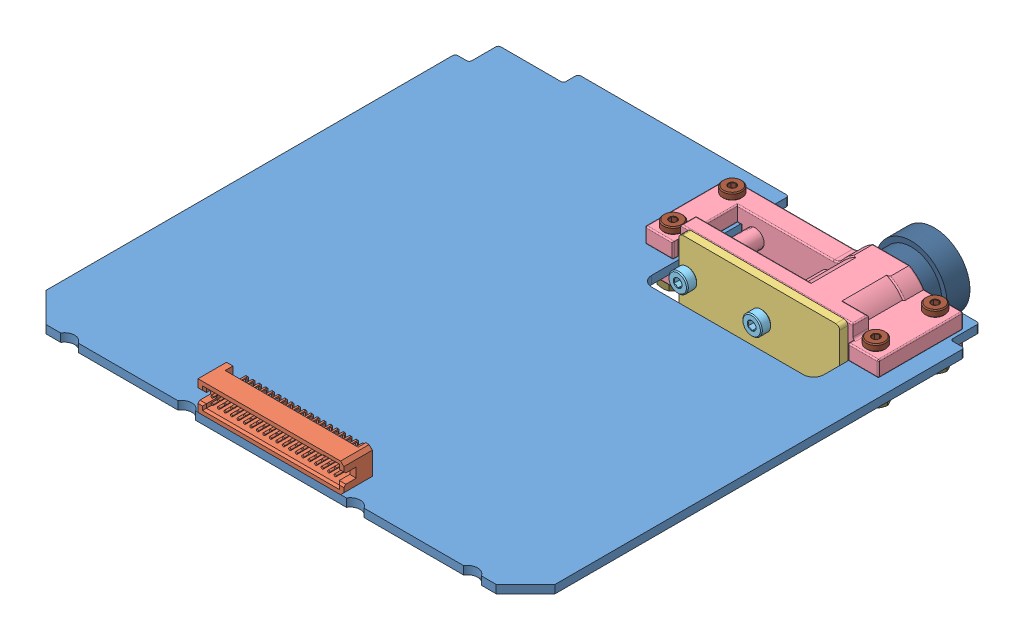
SolidWorks assembly StarTrackerCard, configuration Default. Lengths in mm.
Overall size (100 14.75 109.9).
21 component instances, 12 part files, 45 mates.
Components (placement in the parent):
- StarTrackerCard-1: StarTrackerCard [Default] at origin size (100 12.1 107.37)
- TFM_120_01_L_D_RA_defeature-1: TFM_120_01_L_D_RA_defeature [Default] at (0 3.6575 39.237) x (1 0 0) z (0 -1 0) size (28.58 7.49 7.62)
- startracker-2: startracker [Default] at (23.9 -0.05 -30.1) size (45.75 14.75 27.61)
  - startrackerboard-1: startrackerboard [Default] at (0 -0.2 2.3) x (-1 0 0) z (0 0 -1) size (31.5 13.6 1.6)
  - startrackerboardmount-1: startrackerboardmount [Default] x (-1 0 0) z (0 0 1) size (45.75 14.75 16.6)
  - 92290A850_SUPER-CORROSION-RST 316 SS SCKT HEAD SCREW-1: 92290A850_SUPER-CORROSION-RST 316 SS SCKT HEAD SCREW [92290A850] at (0.5 0 -14.9) x (1 0 0) z (0 0 -1) size (3.8 3.8 20.17)
  - 92290A850_SUPER-CORROSION-RST 316 SS SCKT HEAD SCREW-2: 92290A850_SUPER-CORROSION-RST 316 SS SCKT HEAD SCREW [92290A850] at (-14 0 -14.9) x (-1 0 0) z (0 0 -1) size (3.8 3.8 20.17)
  - 94150A115_316 STAINLESS STEEL HEX NUT-1: 94150A115_316 STAINLESS STEEL HEX NUT [94150A115] at (0.5 0 -13.05) x (-0.5 0.866025 0) z (0 0 1) size (3.2 3.7 1.58)
  - 94150A115_316 STAINLESS STEEL HEX NUT-2: 94150A115_316 STAINLESS STEEL HEX NUT [94150A115] at (-14 0 -13.05) x (0.5 0.866025 0) z (0 0 1) size (3.2 3.7 1.58)
  - ILCC48-1: ILCC48 [Default] at (8.75 0 1.5) x (-1 0 0) z (0 0 -1) size (4.8 3.6 0.72)
  - knifeedgebaffle-1: knifeedgebaffle [Default] at (8.75 0 -6.425) x (0 1 0) z (1 0 0) size (12 2 12)
  - ILCC48_cover-1: ILCC48_cover [Default] at (8.75 0 0.25) x (0 1 0) z (0 0 1) size (7 7 1.25)
  - startrackerNEW-1: startrackerNEW [Default] at (8.75 0 -20.925) x (-1 0 0) z (0 0 -1) size (14 14 16)
- 92855A840_18-8 SS LOW-PROFILE SCKT HEAD SCREWS-1: 92855A840_18-8 SS LOW-PROFILE SCKT HEAD SCREWS [92855A840] at (3.9 -6.15 -41.7) x (1 0 0) z (0 -1 0) size (3.8 3.8 11.46)
- 91828A111_TYPE 18-8 STAINLESS STEEL HEX NUT-2: 91828A111_TYPE 18-8 STAINLESS STEEL HEX NUT [91828A111] at (3.9 -4.75 -41.7) x (0.866025 0 0.5) z (0 -1 0) size (4 4.62 1.83)
- 92855A840_18-8 SS LOW-PROFILE SCKT HEAD SCREWS-5: 92855A840_18-8 SS LOW-PROFILE SCKT HEAD SCREWS [92855A840] at (43.65 -6.15 -41.7) x (1 0 0) z (0 -1 0) size (3.8 3.8 11.46)
- 92855A840_18-8 SS LOW-PROFILE SCKT HEAD SCREWS-6: 92855A840_18-8 SS LOW-PROFILE SCKT HEAD SCREWS [92855A840] at (3.9 -6.15 -30.1) x (1 0 0) z (0 -1 0) size (3.8 3.8 11.46)
- 92855A840_18-8 SS LOW-PROFILE SCKT HEAD SCREWS-7: 92855A840_18-8 SS LOW-PROFILE SCKT HEAD SCREWS [92855A840] at (43.65 -6.15 -30.1) x (1 0 0) z (0 -1 0) size (3.8 3.8 11.46)
- 91828A111_TYPE 18-8 STAINLESS STEEL HEX NUT-4: 91828A111_TYPE 18-8 STAINLESS STEEL HEX NUT [91828A111] at (43.65 -4.75 -41.7) x (0.866025 0 0.5) z (0 -1 0) size (4 4.62 1.83)
- 91828A111_TYPE 18-8 STAINLESS STEEL HEX NUT-5: 91828A111_TYPE 18-8 STAINLESS STEEL HEX NUT [91828A111] at (3.9 -4.75 -30.1) x (0.866025 0 0.5) z (0 -1 0) size (4 4.62 1.83)
- 91828A111_TYPE 18-8 STAINLESS STEEL HEX NUT-6: 91828A111_TYPE 18-8 STAINLESS STEEL HEX NUT [91828A111] at (43.65 -4.75 -30.1) x (0.866025 0 0.5) z (0 -1 0) size (4 4.62 1.83)
Mates (geometry in assembly coordinates):
- Coincident7: coincident: line of StarTrackerCard-1 through (0 0.8 -5.2282) axis (0 0 1); plane of TFM_120_01_L_D_RA_defeature-1 through (0 3.6575 39.237) normal (1 0 0)
- Coincident8: coincident anti-aligned: plane of StarTrackerCard-1 through (0 0.8 0) normal (0 1 0); plane of TFM_120_01_L_D_RA_defeature-1 through (-14.2875 0.8 44.825) normal (0 -1 0)
- Coincident9: coincident: line of StarTrackerCard-1 through (49.9 0.8 37.332) axis (-1 0 0); plane of TFM_120_01_L_D_RA_defeature-1 through (0 3.6575 37.332) normal (0 0 -1)
- Coincident10: coincident aligned: plane of StarTrackerCard-1 through (0 0 0) normal (0 0 1); plane of assembly through (0 0 0) normal (0 0 1)
- Coincident11: coincident aligned: plane of StarTrackerCard-1 through (0 0 0) normal (0 1 0); plane of assembly through (0 0 0) normal (0 1 0)
- Coincident12: coincident aligned: plane of StarTrackerCard-1 through (0 0 0) normal (1 0 0); plane of assembly through (0 0 0) normal (1 0 0)
- Coincident20: coincident anti-aligned: plane of StarTrackerCard-1 through (0 0.8 0) normal (0 1 0); plane of startracker-2/startrackerboardmount-1 through (23.9 0.8 -30.1) normal (0 -1 0)
- Concentric7: concentric anti-aligned: circle of 92290A602_TYPE 316 SS SOCKET HEAD CAP SCREW-2; circle of startracker-2/startrackerboardmount-1
- Coincident21: coincident anti-aligned: plane of 92290A602_TYPE 316 SS SOCKET HEAD CAP SCREW-2 through (3.9 3.8 -42.8) normal (0 -1 0); plane of startracker-2/startrackerboardmount-1 through (6.9 3.85 -28.6) normal (0 1 0)
- Concentric8: concentric anti-aligned: circle of 92290A602_TYPE 316 SS SOCKET HEAD CAP SCREW-1; circle of startracker-2/startrackerboardmount-1
- Coincident22: coincident anti-aligned: plane of 92290A602_TYPE 316 SS SOCKET HEAD CAP SCREW-1 through (3.9 3.8 -31.2) normal (0 -1 0); plane of startracker-2/startrackerboardmount-1 through (6.9 3.85 -28.6) normal (0 1 0)
- Parallel6: parallel anti-aligned: plane of StarTrackerCard-1 through (-34.4 -0.801 -49.8) normal (0 0 -1); plane of 92290A602_TYPE 316 SS SOCKET HEAD CAP SCREW-1 through (3.9 -6.2 -31.2) normal (0 0 1)
- Parallel7: parallel anti-aligned: plane of StarTrackerCard-1 through (-34.4 -0.801 -49.8) normal (0 0 -1); plane of 92290A602_TYPE 316 SS SOCKET HEAD CAP SCREW-2 through (3.9 -6.2 -42.8) normal (0 0 1)
- Coincident23: coincident anti-aligned: plane of 94150A115_316 STAINLESS STEEL HEX NUT-1 through (2.9762 -3.95 -32.8) normal (0 1 0); plane of startracker-2/startrackerboardmount-1 through (3.9 -3.95 -28.6) normal (0 -1 0)
- Concentric9: concentric anti-aligned: circle of 94150A115_316 STAINLESS STEEL HEX NUT-1; circle of startracker-2/startrackerboardmount-1
- Parallel9: parallel aligned: plane of StarTrackerCard-1 through (-34.4 -0.801 -49.8) normal (0 0 -1); plane of 94150A115_316 STAINLESS STEEL HEX NUT-1 through (4.8238 -3.95 -32.8) normal (0 0 -1)
- Concentric10: concentric anti-aligned: circle of 94150A115_316 STAINLESS STEEL HEX NUT-2; circle of startracker-2/startrackerboardmount-1
- Coincident24: coincident anti-aligned: plane of 94150A115_316 STAINLESS STEEL HEX NUT-2 through (2.9762 -3.95 -44.4) normal (0 1 0); plane of startracker-2/startrackerboardmount-1 through (3.9 -3.95 -28.6) normal (0 -1 0)
- Parallel10: parallel aligned: plane of StarTrackerCard-1 through (-34.4 -0.801 -49.8) normal (0 0 -1); plane of 94150A115_316 STAINLESS STEEL HEX NUT-2 through (4.8238 -3.95 -44.4) normal (0 0 -1)
- Distance3: distance = 3.25 mm aligned: plane of StarTrackerCard-1 through (49.9 -0.8 0) normal (1 0 0); plane of startracker-2/startrackerboardmount-1 through (46.65 -0.05 -20.8918) normal (1 0 0)
- Distance1: distance = 5.6 mm aligned: plane of startracker-2/startrackerboardmount-1 through (0.9 -9.3583 -44.2) normal (0 0 -1); plane of StarTrackerCard-1 through (-34.4 -0.801 -49.8) normal (0 0 -1)
- Coincident25: coincident anti-aligned: circle of startracker-2/startrackerboardmount-1; plane of 92290A602_TYPE 316 SS SOCKET HEAD CAP SCREW-4 through (43.65 3.85 -31.2) normal (0 -1 0)
- Concentric11: concentric anti-aligned: circle of startracker-2/startrackerboardmount-1; circle of 92290A602_TYPE 316 SS SOCKET HEAD CAP SCREW-4
- Concentric12: concentric: circle of startracker-2/startrackerboardmount-1; circle of 92290A602_TYPE 316 SS SOCKET HEAD CAP SCREW-3
- Coincident26: coincident anti-aligned: plane of startracker-2/startrackerboardmount-1 through (23.9 3.85 -20.8918) normal (0 1 0); plane of 92290A602_TYPE 316 SS SOCKET HEAD CAP SCREW-3 through (43.65 3.85 -42.8) normal (0 -1 0)
- Parallel11: parallel: plane of startracker-2/startrackerboardmount-1 through (0.9 -9.3583 -44.2) normal (0 0 -1); plane of 92290A602_TYPE 316 SS SOCKET HEAD CAP SCREW-3 through (43.65 -6.15 -42.8) normal (0 0 1)
- Concentric13: concentric anti-aligned: circle of startracker-2/startrackerboardmount-1; circle of 94150A115_316 STAINLESS STEEL HEX NUT-3
- Coincident29: coincident anti-aligned: plane of startracker-2/startrackerboardmount-1 through (23.9 -3.95 -21.8918) normal (0 -1 0); plane of 94150A115_316 STAINLESS STEEL HEX NUT-3 through (42.7262 -3.95 -44.4) normal (0 1 0)
- Concentric14: concentric aligned: circle of startracker-2/startrackerboardmount-1; circle of 94150A115_316 STAINLESS STEEL HEX NUT-4
- Coincident30: coincident anti-aligned: plane of startracker-2/startrackerboardmount-1 through (23.9 -3.95 -21.8918) normal (0 -1 0); plane of 94150A115_316 STAINLESS STEEL HEX NUT-4 through (42.7262 -3.95 -32.8) normal (0 1 0)
- Parallel13: parallel aligned: plane of startracker-2/startrackerboardmount-1 through (23.9 -0.05 -31.6) normal (0 0 -1); plane of 94150A115_316 STAINLESS STEEL HEX NUT-4 through (44.5738 -3.95 -32.8) normal (0 0 -1)
- Parallel14: parallel aligned: plane of startracker-2/startrackerboardmount-1 through (32.65 -0.05 -43.2) normal (0 0 -1); plane of 94150A115_316 STAINLESS STEEL HEX NUT-3 through (44.5738 -3.95 -44.4) normal (0 0 -1)
- Coincident31: coincident anti-aligned: plane of startracker-2/startrackerboardmount-1 through (6.9 3.85 -28.6) normal (0 1 0); plane of 92855A840_18-8 SS LOW-PROFILE SCKT HEAD SCREWS-1 through (3.9 3.85 -41.7) normal (0 -1 0)
- Concentric15: concentric aligned: circle of startracker-2/startrackerboardmount-1; circle of 92855A840_18-8 SS LOW-PROFILE SCKT HEAD SCREWS-1
- Coincident32: coincident anti-aligned: plane of startracker-2/startrackerboardmount-1 through (3.9 -3.95 -28.6) normal (0 -1 0); plane of 93625A101_TYPE 18-8 STAINLESS STL NYLON-INSERT LOCKNUT-1 through (7.469 -3.95 -44.6062) normal (0 1 0)
- Concentric16: concentric aligned: circle of startracker-2/startrackerboardmount-1; circle of 93625A101_TYPE 18-8 STAINLESS STL NYLON-INSERT LOCKNUT-1
- Parallel16: parallel aligned: plane of 92855A840_18-8 SS LOW-PROFILE SCKT HEAD SCREWS-1 through (3.9 -6.15 -41.7) normal (0 0 1)
- Coincident35: coincident anti-aligned: plane of startracker-2/startrackerboardmount-1 through (3.9 -3.95 -28.6) normal (0 -1 0); plane of 91828A111_TYPE 18-8 STAINLESS STEEL HEX NUT-1 through (2.7453 -3.95 -29.2) normal (0 1 0)
- Concentric17: concentric anti-aligned: circle of startracker-2/startrackerboardmount-1; circle of 91828A111_TYPE 18-8 STAINLESS STEEL HEX NUT-1
- Parallel17: parallel aligned: plane of startracker-2/startrackerboardmount-1 through (23.9 -22.2045 -27.6) normal (0 0 1); plane of 91828A111_TYPE 18-8 STAINLESS STEEL HEX NUT-1 through (5.0547 -5.55 -29.2) normal (0 0 1)
- Concentric18: concentric anti-aligned: circle of startracker-2/startrackerboardmount-1; circle of 92855A841_18-8 SS LOW-PROFILE SCKT HEAD SCREWS-1
- Coincident37: coincident anti-aligned: plane of startracker-2/startrackerboardmount-1 through (6.9 3.85 -28.6) normal (0 1 0); plane of 92855A841_18-8 SS LOW-PROFILE SCKT HEAD SCREWS-1 through (3.9 3.85 -31.2) normal (0 -1 0)
- Coincident38: coincident anti-aligned: plane of startracker-2/startrackerboardmount-1 through (3.9 -3.95 -28.6) normal (0 -1 0); plane of 91828A111_TYPE 18-8 STAINLESS STEEL HEX NUT-2 through (1.5906 -3.95 -41.7) normal (0 1 0)
- Concentric19: concentric anti-aligned: circle of startracker-2/startrackerboardmount-1; circle of 91828A111_TYPE 18-8 STAINLESS STEEL HEX NUT-2
- Parallel18: parallel aligned: plane of startracker-2/startrackerboardmount-1 through (0.9 -9.3583 -44.2) normal (0 0 -1); plane of 91828A111_TYPE 18-8 STAINLESS STEEL HEX NUT-2 through (2.7453 -5.55 -43.7) normal (0 0 -1)
